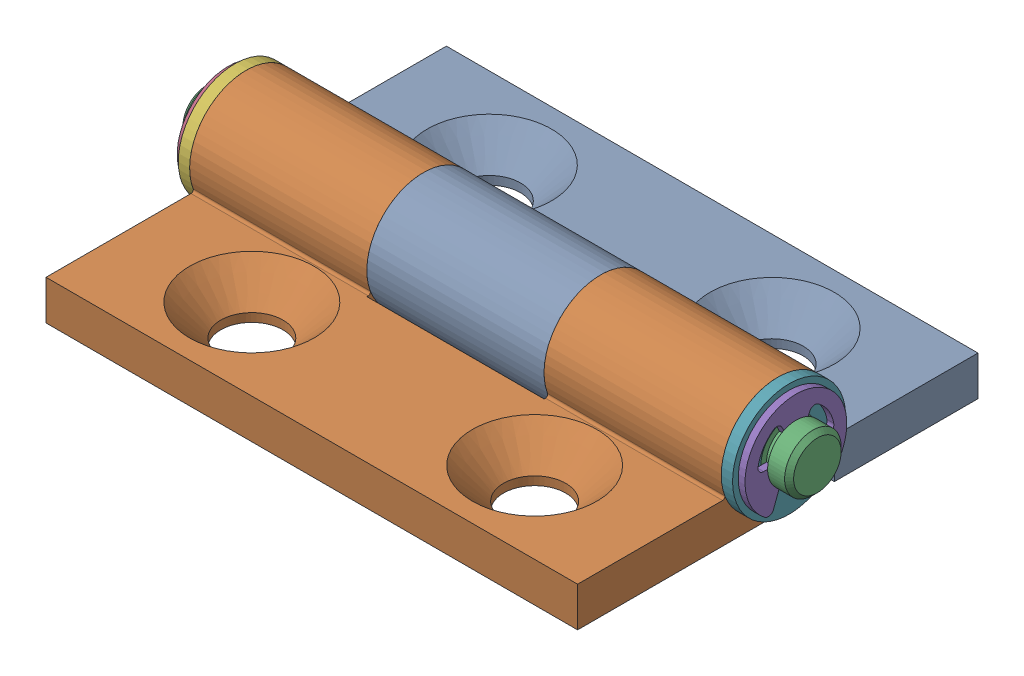
SolidWorks assembly MISUMI_C-HHFL5-2, configuration Default. Lengths in mm.
Overall size (54 10.5 35.4).
7 component instances, 5 part files, 22 mates.
Components (placement in the parent):
- BASE-L_MISUMI_C-HHFL5-2-2: BASE-L_MISUMI_C-HHFL5-2 [Default] at origin size (47 10.5 22.7)
- BASE-R_MISUMI_C-HHFL5-2-1: BASE-R_MISUMI_C-HHFL5-2 [Default] at origin size (47 10.5 22.7)
- SHAFT_MISUMI_C-HHFL5-2-1: SHAFT_MISUMI_C-HHFL5-2 [Default] at (-12.6 5.5 10.5) x (1 0 0) z (0 0 -1) size (54 5 5)
- ERING_MISUMI_C-HHFL5-2-1: ERING_MISUMI_C-HHFL5-2 [Default] at (-12.6 5.5 10.5) size (0.6 8.16 9)
- ERING_MISUMI_C-HHFL5-2-2: ERING_MISUMI_C-HHFL5-2 [Default] at (37 5.5 10.5) size (0.6 8.16 9)
- SPACER_MISUMI_C-HHFL5-2-1: SPACER_MISUMI_C-HHFL5-2 [Default] at (-12 5.5 10.5) size (1 10 10)
- SPACER_MISUMI_C-HHFL5-2-4: SPACER_MISUMI_C-HHFL5-2 [Default] at (36 5.5 10.5) size (1 10 10)
Mates (geometry in assembly coordinates):
- Coincident1: coincident aligned: line of SHAFT_BaseModel20250106083817-1 through (37 5.5 10.5) axis (-1 0 0); line of ERING_BaseModel20250106083817-1 through (-12 5.5 10.5) axis (-1 0 0)
- Coincident2: coincident aligned: line of SHAFT_BaseModel20250106083817-1 through (37 5.5 10.5) axis (-1 0 0); line of ERING_BaseModel20250106083817-2 through (37.6 5.5 10.5) axis (-1 0 0)
- Coincident3: coincident anti-aligned: plane of SHAFT_BaseModel20250106083817-1 through (-12.6 3 10.5) normal (1 0 0); plane of ERING_BaseModel20250106083817-1 through (-12.6 6 7.6434) normal (-1 0 0)
- Coincident4: coincident anti-aligned: plane of SHAFT_BaseModel20250106083817-1 through (37.6 3 10.5) normal (-1 0 0); plane of ERING_BaseModel20250106083817-2 through (37.6 6 7.6434) normal (1 0 0)
- Parallel1: parallel aligned: plane of ERING_BaseModel20250106083817-2 through (37 5.5 10.5) normal (0 1 0)
- Parallel2: parallel aligned: plane of SPACER_BaseModel20250106083817-1 through (-12 5.5 10.5) normal (0 1 0)
- Parallel3: parallel anti-aligned: plane of SHAFT_BaseModel20250106083817-1 through (-12.6 5.5 10.5) normal (0 -1 0)
- Parallel4: parallel aligned: plane of ERING_BaseModel20250106083817-1 through (-12.6 5.5 10.5) normal (0 1 0)
- Coincident5: coincident aligned: line of SHAFT_BaseModel20250106083817-1 through (37 5.5 10.5) axis (-1 0 0); line of SPACER_BaseModel20250106083817-1 through (-11 5.5 10.5) axis (-1 0 0)
- Coincident6: coincident anti-aligned: plane of BASE-L_BaseModel20250106083817-2 through (-11 0 0) normal (-1 0 0); plane of SPACER_BaseModel20250106083817-1 through (-11 8 10.5) normal (1 0 0)
- Coincident7: coincident anti-aligned: plane of ERING_BaseModel20250106083817-1 through (-12 6 7.6434) normal (1 0 0); plane of SPACER_BaseModel20250106083817-1 through (-12 10.5 10.5) normal (-1 0 0)
- Coincident8: coincident aligned: plane of BASE-R_BaseModel20250106083817-1 through (0 0 0) normal (1 0 0)
- Coincident9: coincident aligned: plane of BASE-L_BaseModel20250106083817-2 through (0 0 0) normal (0 0 1)
- Coincident10: coincident aligned: plane of BASE-L_BaseModel20250106083817-2 through (0 0 0) normal (0 1 0)
- Coincident11: coincident aligned: plane of BASE-L_BaseModel20250106083817-2 through (0 0 0) normal (1 0 0)
- Coincident12: coincident aligned: plane of BASE-R_BaseModel20250106083817-1 through (0 0 0) normal (1 0 0)
- Coincident13: coincident aligned: line of BASE-L_BaseModel20250106083817-2 through (20.3333 5.5 10.5) axis (-1 0 0); line of SHAFT_BaseModel20250106083817-1 through (37 5.5 10.5) axis (-1 0 0)
- Coincident14: coincident aligned: line of BASE-R_BaseModel20250106083817-1 through (4.6667 5.5 10.5) axis (-1 0 0); line of SHAFT_BaseModel20250106083817-1 through (37 5.5 10.5) axis (-1 0 0)
- Concentric3: concentric aligned: cylinder of SPACER_BaseModel20250106083817-1 through (-12.05 5.5 10.5) axis (-1 0 0) radius 5; cylinder of SPACER_BaseModel20250106083817-4 through (35.95 5.5 10.5) axis (-1 0 0) radius 5
- Parallel5: parallel aligned: plane of SPACER_BaseModel20250106083817-1 through (-12 5.5 10.5) normal (0 0 1)
- Parallel8: parallel aligned: plane of SPACER_BaseModel20250106083817-4 through (36 5.5 10.5) normal (0 0 1)
- Coincident15: coincident anti-aligned: plane of ERING_BaseModel20250106083817-2 through (37 6 7.6434) normal (-1 0 0); plane of SPACER_BaseModel20250106083817-4 through (37 8 10.5) normal (1 0 0)
